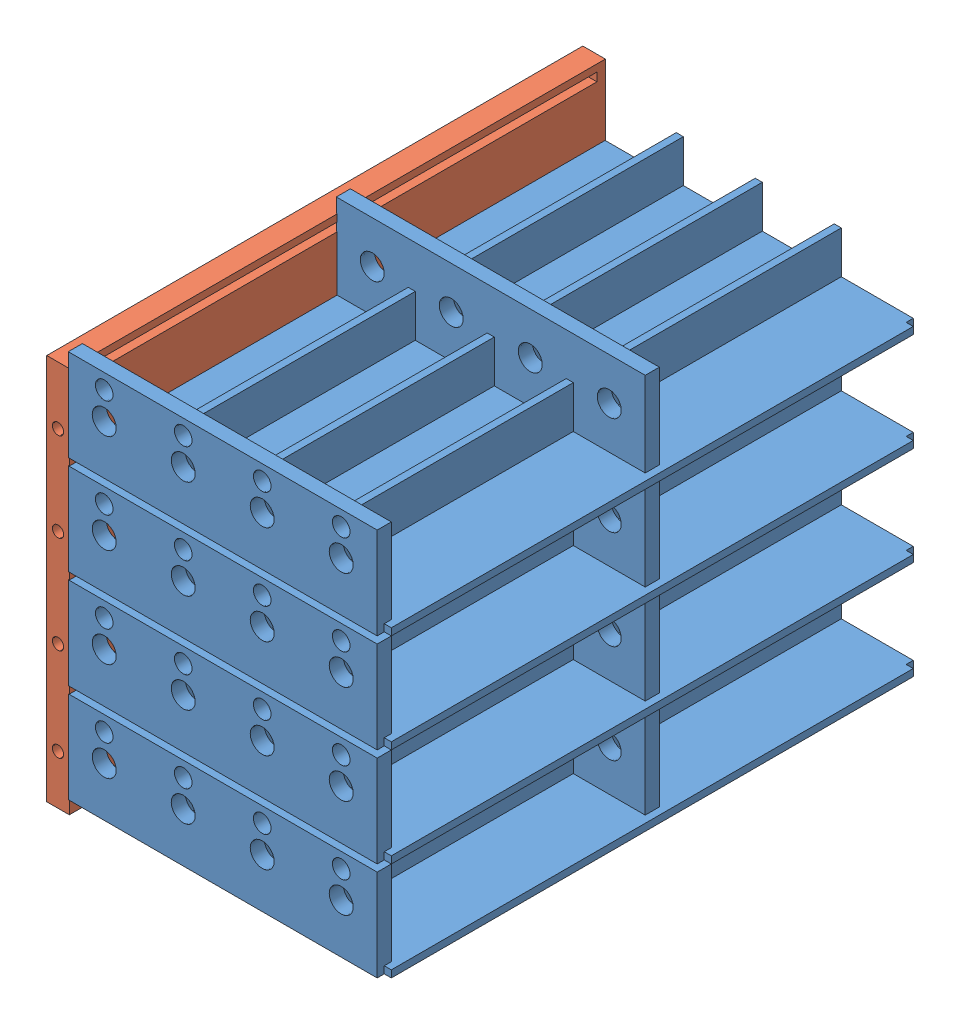
SolidWorks assembly Motor Box, configuration Default. Lengths in mm.
Overall size (47.88 56.83 76.03).
5 component instances, 2 part files, 0 mates.
Components (placement in the parent):
- Guide Frame x4-1: Guide Frame x4 [Default] at (60.9736 5.9438 69.3147) size (45.8 13 76)
- Guide Frame x4-2: Guide Frame x4 [Default] at (60.9736 19.9438 69.3147) size (45.8 13 76)
- Guide Frame x4-3: Guide Frame x4 [Default] at (60.9736 33.9438 69.3147) size (45.8 13 76)
- Guide Frame x4-4: Guide Frame x4 [Default] at (60.9736 47.9438 69.3147) size (45.8 13 76)
- Guide Frame Right-1: Guide Frame Right [Default] at (22.185 73.7538 69.2811) x (0 0 1) z (1 0 0) size (76 54.8 3.2)
